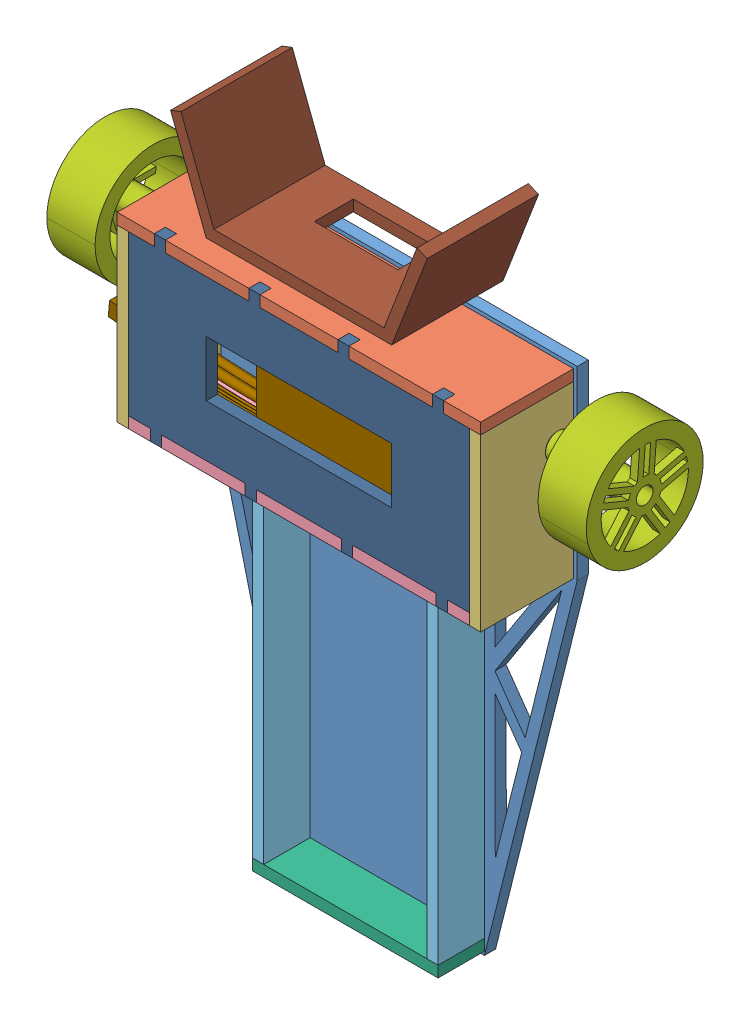
SolidWorks assembly Assembly, configuration 기본. Lengths in mm.
Overall size (290.8 362.15 151.94).
15 component instances, 11 part files, 40 mates.
Components (placement in the parent):
- bottom-1: bottom [기본] at (12.4042 -169.8861 297) size (200 300 6)
- frontWall-1: frontWall [기본] at (12.4042 122.1139 303) size (196 6 151.94)
- sideWall x2-4: sideWall x2 [기본] at (110.4042 76.1139 303) x (0 1 0) z (0 0 1) size (92 6 56)
- sideWall x2-5: sideWall x2 [기본] at (-79.5958 76.1139 303) x (0 1 0) z (0 0 1) size (92 6 56)
- midWall-1: midWall [기본] at (12.4042 30.1139 303) x (-1 0 0) z (0 1 0) size (184 56 6)
- midWall_2 x2-1: midWall_2 x2 [기본] at (56.4042 -65.8861 303) x (0 -1 0) z (0 0 1) size (192 6 31)
- midWall_2 x2-2: midWall_2 x2 [기본] at (-37.5958 -65.8861 303) x (0 -1 0) z (0 0 1) size (192 6 31)
- backWall-1: backWall [기본] at (12.4042 -167.8861 303) size (100 6 31)
- wheel-basic.step-1: wheel-basic.step [기본] at (157.8042 97.1139 312) x (0 0.971341 0.237689) z (0 -0.237689 0.971341) size (63 46.5 63)
- wheel-basic.step-2: wheel-basic.step [기본] at (-132.9958 97.1139 312) x (0 -1 0) z (0 0 1) size (63 46.5 63)
- motor.step-1: motor.step [기본] at (53.0042 103.5639 321.0337) x (0 0.813846 -0.581081) z (0 -0.581081 -0.813846) size (37.1 151.83 37.1)
- motor.step-2: motor.step [기본] at (-28.1958 103.5639 321.0337) x (0 -0.813846 0.581081) z (0 -0.581081 -0.813846) size (37.1 151.83 37.1)
- lipo-battery.stp-1: lipo-battery.stp [기본] at (278.1425 -234.201 328) x (0 -1 0) z (0 0 -1) size (45 230.34 25)
- topCover-1: topCover [기본] at (12.4042 36.1139 347) size (184 98 6)
- Grabber-1: Grabber [기본] at (12.4042 140.1139 293) size (138.41 70.15 60)
Mates (geometry in assembly coordinates):
- Coincident1: coincident aligned: plane of bottom-1 through (12.4042 -169.8861 297) normal (0 0 -1); plane of frontWall-1 through (12.4042 122.1139 297) normal (0 0 -1)
- Coincident3: coincident anti-aligned: plane of bottom-1 through (104.4042 122.1139 303) normal (0 1 0); plane of frontWall-1 through (110.4042 122.1139 353) normal (0 -1 0)
- Coincident4: coincident anti-aligned: plane of bottom-1 through (104.4042 128.1139 303) normal (-1 0 0); plane of frontWall-1 through (104.4042 122.1139 297) normal (1 0 0)
- Coincident6: coincident aligned: plane of bottom-1 through (12.4042 -169.8861 297) normal (0 0 -1); plane of sideWall x2-4 through (110.4042 76.1139 297) normal (0 0 -1)
- Coincident7: coincident anti-aligned: plane of bottom-1 through (104.4042 106.1139 303) normal (1 0 0); plane of sideWall x2-4 through (104.4042 30.1139 353) normal (-1 0 0)
- Coincident8: coincident anti-aligned: plane of bottom-1 through (104.4042 112.1139 303) normal (0 -1 0); plane of sideWall x2-4 through (110.4042 112.1139 297) normal (0 1 0)
- Coincident9: coincident aligned: plane of bottom-1 through (12.4042 -169.8861 297) normal (0 0 -1); plane of sideWall x2-5 through (-79.5958 76.1139 297) normal (0 0 -1)
- Coincident10: coincident anti-aligned: plane of bottom-1 through (-85.5958 40.1139 303) normal (0 1 0); plane of sideWall x2-5 through (-79.5958 40.1139 297) normal (0 -1 0)
- Coincident11: coincident anti-aligned: plane of bottom-1 through (-79.5958 40.1139 303) normal (-1 0 0); plane of sideWall x2-5 through (-79.5958 30.1139 353) normal (1 0 0)
- Coincident12: coincident aligned: plane of bottom-1 through (12.4042 -169.8861 297) normal (0 0 -1); plane of midWall-1 through (12.4042 30.1139 297) normal (0 0 -1)
- Coincident13: coincident anti-aligned: plane of bottom-1 through (-67.5958 36.1139 303) normal (0 -1 0); plane of midWall-1 through (12.4042 36.1139 303) normal (0 1 0)
- Coincident14: coincident anti-aligned: plane of bottom-1 through (-73.5958 36.1139 303) normal (1 0 0); plane of midWall-1 through (-73.5958 36.1139 297) normal (-1 0 0)
- Coincident15: coincident aligned: plane of bottom-1 through (12.4042 -169.8861 297) normal (0 0 -1); plane of midWall_2 x2-2 through (-31.5958 -155.8861 297) normal (0 0 -1)
- Coincident16: coincident anti-aligned: plane of bottom-1 through (-31.5958 -98.8861 303) normal (-1 0 0); plane of midWall_2 x2-2 through (-31.5958 30.1139 328) normal (1 0 0)
- Coincident17: coincident anti-aligned: plane of bottom-1 through (-37.5958 -149.8861 303) normal (0 -1 0); plane of midWall_2 x2-2 through (-31.5958 -149.8861 297) normal (0 1 0)
- Coincident18: coincident aligned: plane of bottom-1 through (12.4042 -169.8861 297) normal (0 0 -1); plane of midWall_2 x2-1 through (62.4042 -155.8861 297) normal (0 0 -1)
- Coincident19: coincident anti-aligned: plane of bottom-1 through (62.4042 -104.8861 303) normal (-1 0 0); plane of midWall_2 x2-1 through (62.4042 30.1139 328) normal (1 0 0)
- Coincident20: coincident anti-aligned: plane of bottom-1 through (62.4042 -149.8861 303) normal (0 -1 0); plane of midWall_2 x2-1 through (62.4042 -149.8861 297) normal (0 1 0)
- Coincident21: coincident aligned: plane of bottom-1 through (12.4042 -169.8861 297) normal (0 0 -1); plane of backWall-1 through (12.4042 -167.8861 297) normal (0 0 -1)
- Coincident22: coincident anti-aligned: plane of bottom-1 through (56.4042 -167.8861 303) normal (0 1 0); plane of backWall-1 through (62.4042 -167.8861 328) normal (0 -1 0)
- Coincident23: coincident anti-aligned: plane of bottom-1 through (56.4042 -161.8861 303) normal (-1 0 0); plane of backWall-1 through (56.4042 -161.8861 297) normal (1 0 0)
- Concentric3: concentric: cylinder of sideWall x2-4 through (104.4042 97.1139 312) axis (1 0 0) radius 6; cylinder of motor.step-1 through (111.3042 97.1139 312) axis (-1 0 0) radius 6
- Coincident28: coincident: plane of sideWall x2-4 through (104.4042 30.1139 353) normal (-1 0 0); plane of motor.step-1 through (104.4042 103.5639 321.0337) normal (1 0 0)
- Concentric4: concentric: cylinder of sideWall x2-5 through (-85.5958 97.1139 312) axis (1 0 0) radius 6; cylinder of motor.step-2 through (-86.4958 97.1139 312) axis (1 0 0) radius 6
- Coincident29: coincident: plane of sideWall x2-5 through (-79.5958 30.1139 353) normal (1 0 0); plane of motor.step-2 through (-79.5958 103.5639 321.0337) normal (-1 0 0)
- Tangent3: tangent: plane of frontWall-1 through (110.4042 122.1139 353) normal (0 -1 0); cylinder of motor.step-1 through (104.4042 103.5639 321.0337) axis (-1 0 0) radius 18.55
- Tangent4: tangent: plane of frontWall-1 through (110.4042 122.1139 353) normal (0 -1 0); cylinder of motor.step-2 through (-79.5958 103.5639 321.0337) axis (1 0 0) radius 18.55
- Coincident30: coincident: plane of wheel-basic.step-1 through (111.3042 97.1139 312) normal (-1 0 0); plane of motor.step-1 through (111.3042 97.1139 312) normal (1 0 0)
- Concentric5: concentric: cylinder of wheel-basic.step-1 through (111.3042 97.1139 312) axis (1 0 0) radius 4.5; cylinder of motor.step-1 through (126.8042 97.1139 312) axis (-1 0 0) radius 2.95
- Coincident31: coincident: plane of wheel-basic.step-2 through (-86.4958 97.1139 312) normal (1 0 0); plane of motor.step-2 through (-86.4958 97.1139 312) normal (-1 0 0)
- Concentric7: concentric: cylinder of wheel-basic.step-2 through (-86.4958 97.1139 312) axis (-1 0 0) radius 4.5; cylinder of motor.step-2 through (-101.9958 97.1139 312) axis (1 0 0) radius 2.95
- Coincident32: coincident: plane of sideWall x2-4 through (104.4042 30.1139 353) normal (-1 0 0); plane of lipo-battery.stp-1 through (104.4042 81.1139 328) normal (1 0 0)
- Coincident34: coincident: plane of midWall-1 through (12.4042 36.1139 303) normal (0 1 0); plane of lipo-battery.stp-1 through (104.4042 36.1139 328) normal (0 -1 0)
- Coincident35: coincident: plane of bottom-1 through (12.4042 -169.8861 303) normal (0 0 1); plane of lipo-battery.stp-1 through (104.4042 81.1139 303) normal (0 0 -1)
- Coincident36: coincident anti-aligned: plane of frontWall-1 through (-59.5958 122.1139 347) normal (-1 0 0); plane of topCover-1 through (-59.5958 122.1139 353) normal (1 0 0)
- Coincident37: coincident anti-aligned: plane of midWall-1 through (12.4042 36.1139 303) normal (0 1 0); plane of topCover-1 through (104.4042 36.1139 353) normal (0 -1 0)
- Coincident38: coincident aligned: plane of sideWall x2-5 through (-79.5958 76.1139 353) normal (0 0 1); plane of topCover-1 through (12.4042 36.1139 353) normal (0 0 1)
- Coincident39: coincident anti-aligned: plane of frontWall-1 through (28.9042 128.1139 330.5) normal (1 0 0); plane of Grabber-1 through (28.9042 122.1139 330.5) normal (-1 0 0)
- Coincident40: coincident anti-aligned: plane of frontWall-1 through (28.9042 128.1139 336.5) normal (0 0 -1); plane of Grabber-1 through (28.9042 122.1139 336.5) normal (0 0 1)
- Coincident41: coincident aligned: plane of frontWall-1 through (110.4042 122.1139 353) normal (0 -1 0); plane of Grabber-1 through (12.4042 122.1139 293) normal (0 -1 0)
